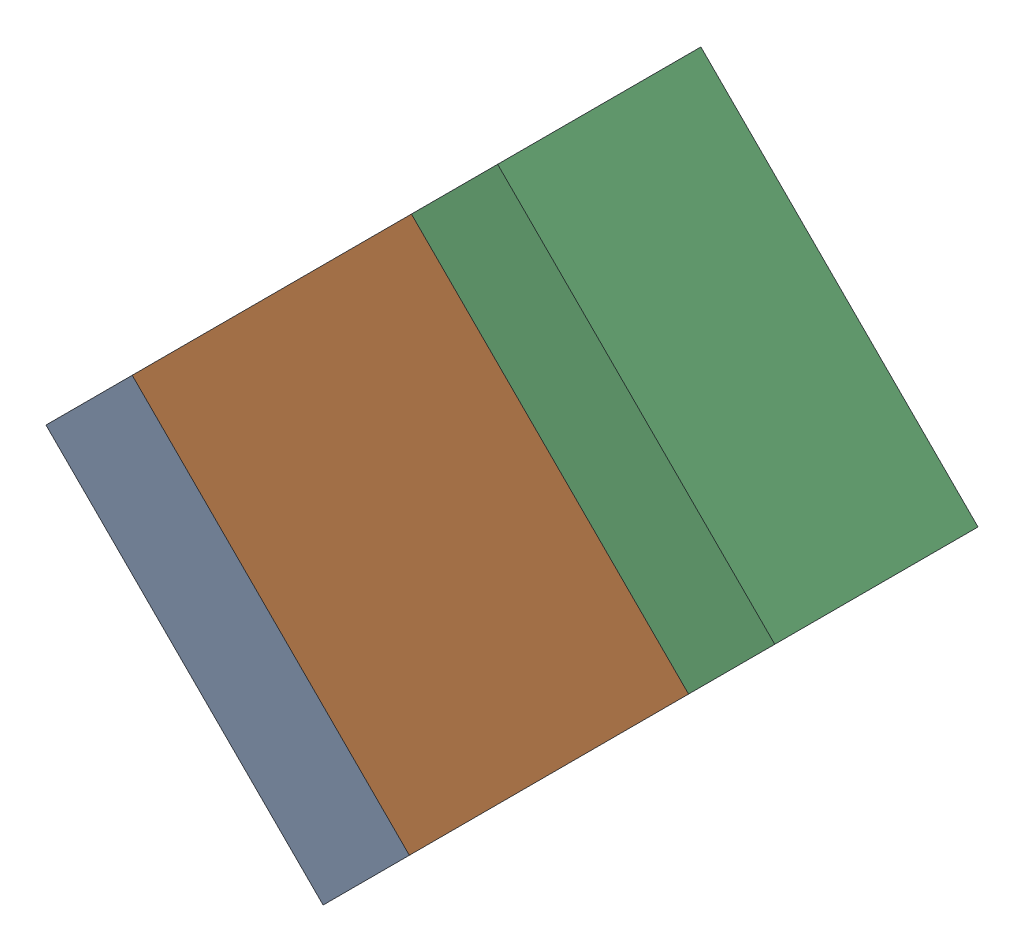
SolidWorks assembly R8-1, configuration Default. Lengths in mm.
Overall size (2.51 2.51 0.7).
6 component instances, 2 part files, 0 mates.
Components (placement in the parent):
- 959207576-1-1: 959207576-1 [Default] at (78.6187 92.1936 0) size (1.25 1.25 0.7)
  - Extruded-54-1: Extruded-54 [Default] at origin size (1.25 1.25 0.7)
- 959207712-1-1: 959207712-1 [Default] at (79.248 92.8229 0) size (1.92 1.92 0.7)
  - Extruded-55-1: Extruded-55 [Default] at origin size (1.92 1.92 0.7)
- 959207576-1-2: 959207576-1 [Default] at (79.8773 93.4522 0) size (1.25 1.25 0.7)
  - Extruded-54-1: Extruded-54 [Default] at origin size (1.25 1.25 0.7)
